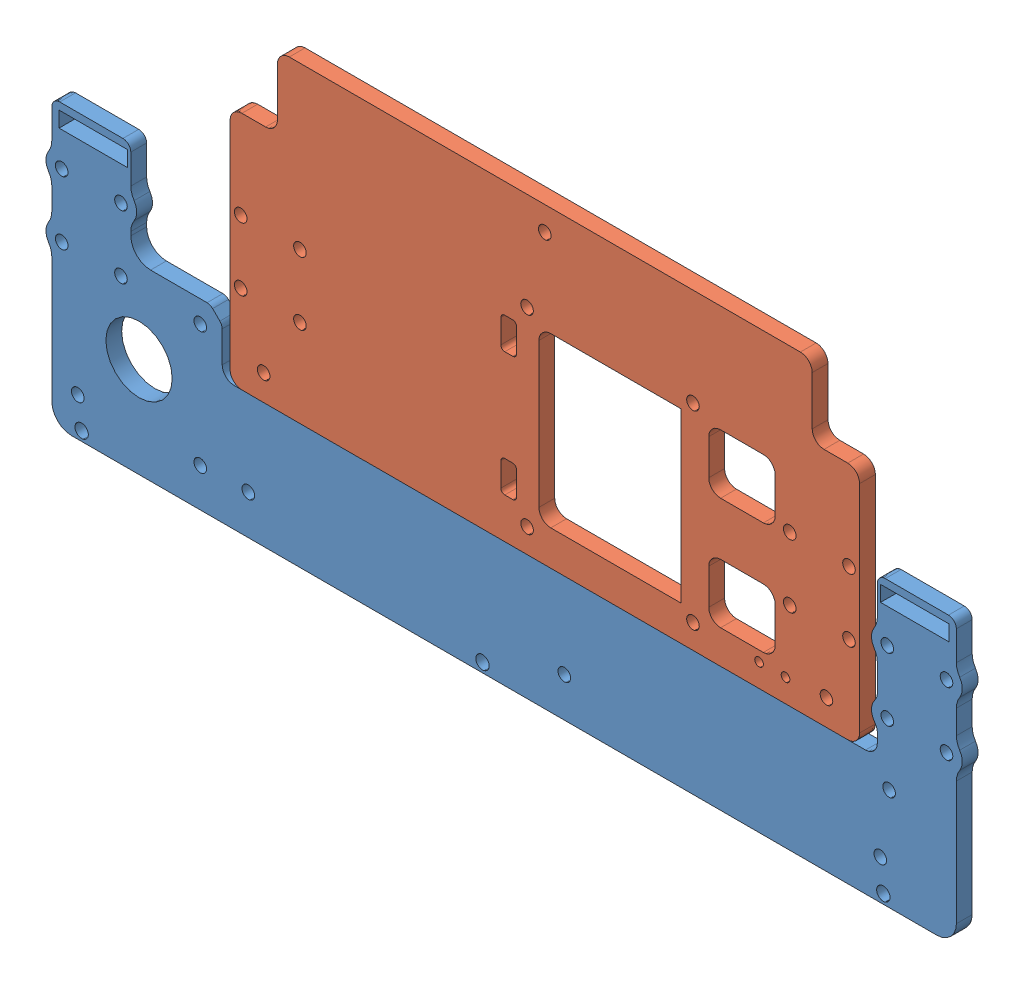
SolidWorks assembly FOOR AND X, configuration Default. Lengths in mm.
Overall size (510.11 215.73 35.34).
2 component instances, 2 part files, 2 mates.
Components (placement in the parent):
- X Bridge 4-1: X Bridge 4 [Valor predeterminado] at (122.7873 139.5223 31.3361) x (-1 0 0) z (0 0 1) size (232 71.67 4)
- Bed Support2-1: Bed Support2 [Default] at (232.6471 167.924 31.3361) x (-1 0 0) z (0 0 1) size (159.38 135.83 4)
Mates (geometry in assembly coordinates):
- Distance2: distance = 3 mm anti-aligned: cylinder of X Bridge 4-1 through (220.3363 106.845 35.3361) axis (0 0 -1) radius 4; plane of Bed Support2-1 through (213.3363 138.2262 25.3361) normal (1 0 0)
- Coincident2: coincident aligned: plane of X Bridge 4-1 through (122.7873 139.5223 35.3361) normal (0 0 1); plane of Bed Support2-1 through (232.6471 167.924 35.3361) normal (0 0 1)
